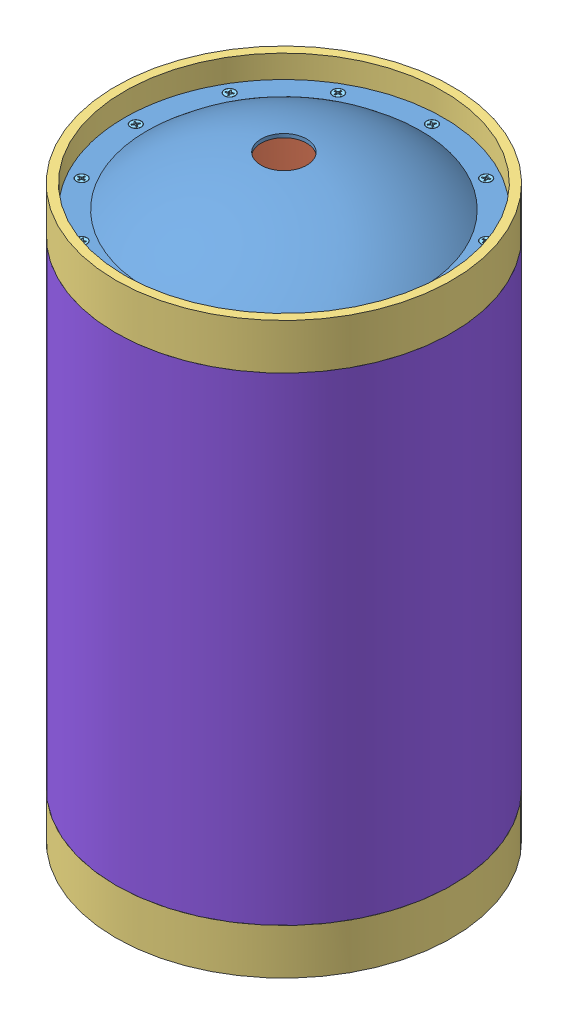
SolidWorks assembly Cryo Tank, configuration Default. Lengths in mm.
Overall size (93.73 173.79 93.73).
34 component instances, 8 part files, 29 mates.
Components (placement in the parent):
- End Cap-1: End Cap [Default] at origin size (88.9 15.46 88.9)
- Liner-1: Liner [Default] at (0 -4.7625 0) size (79.25 133.35 79.25)
- Main Ring-1: Main Ring [Default] at (0 -1.5875 0) size (93.73 25.4 93.73)
- Ring Seal-1: Ring Seal [Default] at (0 -1.5875 0) size (88.9 1.59 88.9)
- Main Ring-2: Main Ring [Default] at (0 -141.2875 0) x (-1 0 0) z (0 0 1) size (93.73 25.4 93.73)
- Ring Seal-2: Ring Seal [Default] at (0 -142.875 0) size (88.9 1.59 88.9)
- End Cap-2: End Cap [Default] at (0 -142.875 0) x (-1 0 0) z (0 0 1) size (88.9 15.46 88.9)
- 90273A015_ZINC-PLATED STL FLAT HEAD PHIL MACHINE SCREW-1: 90273A015_ZINC-PLATED STL FLAT HEAD PHIL MACHINE SCREW [90273A015] at (-35.7452 0.6985 20.6375) x (1 0 0) z (0 1 0) size (2.84 2.84 8.46)
- 90273A015_ZINC-PLATED STL FLAT HEAD PHIL MACHINE SCREW-2: 90273A015_ZINC-PLATED STL FLAT HEAD PHIL MACHINE SCREW [90273A015] at (-41.275 0.6985 0) x (0.866025 0 0.5) z (0 1 0) size (2.84 2.84 8.46)
- 90273A015_ZINC-PLATED STL FLAT HEAD PHIL MACHINE SCREW-3: 90273A015_ZINC-PLATED STL FLAT HEAD PHIL MACHINE SCREW [90273A015] at (-35.7452 0.6985 -20.6375) x (0.5 0 0.866025) z (0 1 0) size (2.84 2.84 8.46)
- 90273A015_ZINC-PLATED STL FLAT HEAD PHIL MACHINE SCREW-4: 90273A015_ZINC-PLATED STL FLAT HEAD PHIL MACHINE SCREW [90273A015] at (-20.6375 0.6985 -35.7452) x (0 0 1) z (0 1 0) size (2.84 2.84 8.46)
- 90273A015_ZINC-PLATED STL FLAT HEAD PHIL MACHINE SCREW-5: 90273A015_ZINC-PLATED STL FLAT HEAD PHIL MACHINE SCREW [90273A015] at (0 0.6985 -41.275) x (-0.5 0 0.866025) z (0 1 0) size (2.84 2.84 8.46)
- 90273A015_ZINC-PLATED STL FLAT HEAD PHIL MACHINE SCREW-6: 90273A015_ZINC-PLATED STL FLAT HEAD PHIL MACHINE SCREW [90273A015] at (20.6375 0.6985 -35.7452) x (-0.866025 0 0.5) z (0 1 0) size (2.84 2.84 8.46)
- 90273A015_ZINC-PLATED STL FLAT HEAD PHIL MACHINE SCREW-7: 90273A015_ZINC-PLATED STL FLAT HEAD PHIL MACHINE SCREW [90273A015] at (35.7452 0.6985 -20.6375) x (-1 0 0) z (0 1 0) size (2.84 2.84 8.46)
- 90273A015_ZINC-PLATED STL FLAT HEAD PHIL MACHINE SCREW-8: 90273A015_ZINC-PLATED STL FLAT HEAD PHIL MACHINE SCREW [90273A015] at (41.275 0.6985 0) x (-0.866025 0 -0.5) z (0 1 0) size (2.84 2.84 8.46)
- 90273A015_ZINC-PLATED STL FLAT HEAD PHIL MACHINE SCREW-9: 90273A015_ZINC-PLATED STL FLAT HEAD PHIL MACHINE SCREW [90273A015] at (35.7452 0.6985 20.6375) x (-0.5 0 -0.866025) z (0 1 0) size (2.84 2.84 8.46)
- 90273A015_ZINC-PLATED STL FLAT HEAD PHIL MACHINE SCREW-10: 90273A015_ZINC-PLATED STL FLAT HEAD PHIL MACHINE SCREW [90273A015] at (20.6375 0.6985 35.7452) x (0 0 -1) z (0 1 0) size (2.84 2.84 8.46)
- 90273A015_ZINC-PLATED STL FLAT HEAD PHIL MACHINE SCREW-11: 90273A015_ZINC-PLATED STL FLAT HEAD PHIL MACHINE SCREW [90273A015] at (0 0.6985 41.275) x (0.5 0 -0.866025) z (0 1 0) size (2.84 2.84 8.46)
- 90273A015_ZINC-PLATED STL FLAT HEAD PHIL MACHINE SCREW-12: 90273A015_ZINC-PLATED STL FLAT HEAD PHIL MACHINE SCREW [90273A015] at (-20.6375 0.6985 35.7452) x (0.866025 0 -0.5) z (0 1 0) size (2.84 2.84 8.46)
- 90273A015_ZINC-PLATED STL FLAT HEAD PHIL MACHINE SCREW-13: 90273A015_ZINC-PLATED STL FLAT HEAD PHIL MACHINE SCREW [90273A015] at (0 -143.5735 41.275) x (1 0 0) z (0 -1 0) size (2.84 2.84 8.46)
- 90273A015_ZINC-PLATED STL FLAT HEAD PHIL MACHINE SCREW-25: 90273A015_ZINC-PLATED STL FLAT HEAD PHIL MACHINE SCREW [90273A015] at (-20.6375 -143.5735 35.7452) x (0.866025 0 0.5) z (0 -1 0) size (2.84 2.84 8.46)
- 90273A015_ZINC-PLATED STL FLAT HEAD PHIL MACHINE SCREW-26: 90273A015_ZINC-PLATED STL FLAT HEAD PHIL MACHINE SCREW [90273A015] at (-35.7452 -143.5735 20.6375) x (0.5 0 0.866025) z (0 -1 0) size (2.84 2.84 8.46)
- 90273A015_ZINC-PLATED STL FLAT HEAD PHIL MACHINE SCREW-27: 90273A015_ZINC-PLATED STL FLAT HEAD PHIL MACHINE SCREW [90273A015] at (-41.275 -143.5735 0) x (0 0 1) z (0 -1 0) size (2.84 2.84 8.46)
- 90273A015_ZINC-PLATED STL FLAT HEAD PHIL MACHINE SCREW-28: 90273A015_ZINC-PLATED STL FLAT HEAD PHIL MACHINE SCREW [90273A015] at (-35.7452 -143.5735 -20.6375) x (-0.5 0 0.866025) z (0 -1 0) size (2.84 2.84 8.46)
- 90273A015_ZINC-PLATED STL FLAT HEAD PHIL MACHINE SCREW-29: 90273A015_ZINC-PLATED STL FLAT HEAD PHIL MACHINE SCREW [90273A015] at (-20.6375 -143.5735 -35.7452) x (-0.866025 0 0.5) z (0 -1 0) size (2.84 2.84 8.46)
- 90273A015_ZINC-PLATED STL FLAT HEAD PHIL MACHINE SCREW-30: 90273A015_ZINC-PLATED STL FLAT HEAD PHIL MACHINE SCREW [90273A015] at (0 -143.5735 -41.275) x (-1 0 0) z (0 -1 0) size (2.84 2.84 8.46)
- 90273A015_ZINC-PLATED STL FLAT HEAD PHIL MACHINE SCREW-31: 90273A015_ZINC-PLATED STL FLAT HEAD PHIL MACHINE SCREW [90273A015] at (20.6375 -143.5735 -35.7452) x (-0.866025 0 -0.5) z (0 -1 0) size (2.84 2.84 8.46)
- 90273A015_ZINC-PLATED STL FLAT HEAD PHIL MACHINE SCREW-32: 90273A015_ZINC-PLATED STL FLAT HEAD PHIL MACHINE SCREW [90273A015] at (35.7452 -143.5735 -20.6375) x (-0.5 0 -0.866025) z (0 -1 0) size (2.84 2.84 8.46)
- 90273A015_ZINC-PLATED STL FLAT HEAD PHIL MACHINE SCREW-33: 90273A015_ZINC-PLATED STL FLAT HEAD PHIL MACHINE SCREW [90273A015] at (41.275 -143.5735 0) x (0 0 -1) z (0 -1 0) size (2.84 2.84 8.46)
- 90273A015_ZINC-PLATED STL FLAT HEAD PHIL MACHINE SCREW-34: 90273A015_ZINC-PLATED STL FLAT HEAD PHIL MACHINE SCREW [90273A015] at (35.7452 -143.5735 20.6375) x (0.5 0 -0.866025) z (0 -1 0) size (2.84 2.84 8.46)
- 90273A015_ZINC-PLATED STL FLAT HEAD PHIL MACHINE SCREW-35: 90273A015_ZINC-PLATED STL FLAT HEAD PHIL MACHINE SCREW [90273A015] at (20.6375 -143.5735 35.7452) x (0.866025 0 -0.5) z (0 -1 0) size (2.84 2.84 8.46)
- CF Inner Layer-1: CF Inner Layer [Default] at (0 64.2407 0) size (80.52 133.35 80.52)
- Honeycomb Core-1: Honeycomb Core [Default] at (0 -50.3801 0) size (93.22 133.35 93.22)
- CF Outer Layer-1: CF Outer Layer [Default] at (0 15.1434 0) size (93.73 133.35 93.73)
Mates (geometry in assembly coordinates):
- Coincident13: coincident: point of Liner-1; point of assembly
- Coincident14: coincident aligned: plane of Liner-1 through (0 -4.7625 0) normal (0 0 1); plane of assembly through (0 0 0) normal (0 0 1)
- Coincident15: coincident aligned: plane of End Cap-1 through (0 0 0) normal (0 0 1); plane of assembly through (0 0 0) normal (0 0 1)
- Coincident16: coordinate: point of End Cap-1; point of assembly
- Coincident17: coincident anti-aligned: line of ? through (110 0 53.4125) axis (0 0 -1)
- Coincident18: coincident aligned: plane of Ring Seal-1 through (0 -1.5875 0) normal (0 0 1); plane of assembly through (0 0 0) normal (0 0 1)
- Coincident20: coincident anti-aligned: line of ? through (110 0 53.4125) axis (0 0 -1)
- Coincident21: coincident aligned: plane of Main Ring-1 through (0 -1.5875 0) normal (0 0 1); plane of assembly through (0 0 0) normal (0 0 1)
- Coincident22: coincident: unknown of ?
- Coincident23: coincident anti-aligned: line of Ring Seal-2 through (110 0 -87.875) axis (0 0 -1); line of assembly
- Coincident24: coincident aligned: plane of Ring Seal-2 through (0 -142.875 0) normal (0 0 1); plane of assembly through (0 0 0) normal (0 0 1)
- Coincident25: coincident: point of Ring Seal-2; point of assembly
- Coincident26: coincident aligned: line of End Cap-2 through (110 0 -197.875) axis (0 0 1); line of assembly
- Coincident27: coincident aligned: plane of End Cap-2 through (0 -142.875 0) normal (0 0 1); plane of assembly through (0 0 0) normal (0 0 1)
- Coincident28: coincident: point of End Cap-2; point of assembly
- Coincident29: coincident aligned: line of Main Ring-2 through (110 0 -196.2875) axis (0 0 1); line of assembly
- Coincident30: coincident aligned: plane of Main Ring-2 through (0 -141.2875 0) normal (0 0 1); plane of assembly through (0 0 0) normal (0 0 1)
- Coincident31: coincident: point of Main Ring-2; point of assembly
- Coincident32: coincident: unknown of ?
- Coincident33: coincident aligned: plane of End Cap-1 through (-44.45 1.5875 0) normal (0 1 0); plane of 90273A015_ZINC-PLATED STL FLAT HEAD PHIL MACHINE SCREW-1 through (-35.7452 1.5875 19.8755) normal (0 1 0)
- Concentric1: concentric anti-aligned: circle of End Cap-1; circle of 90273A015_ZINC-PLATED STL FLAT HEAD PHIL MACHINE SCREW-1
- Concentric2: concentric anti-aligned: circle of End Cap-2; circle of 90273A015_ZINC-PLATED STL FLAT HEAD PHIL MACHINE SCREW-13
- Coincident34: coincident aligned: plane of End Cap-2 through (44.45 -144.4625 0) normal (0 -1 0); plane of 90273A015_ZINC-PLATED STL FLAT HEAD PHIL MACHINE SCREW-13 through (0 -144.4625 42.037) normal (0 -1 0)
- Coincident35: coincident aligned: line of Main Ring-1 through (110 0 53.4125) axis (0 0 -1); line of CF Inner Layer-1 through (110 0 119.2407) axis (0 0 -1)
- Coincident36: coincident aligned: plane of CF Inner Layer-1 through (0 64.2407 0) normal (0 0 1); plane of assembly through (0 0 0) normal (0 0 1)
- Coincident37: coincident aligned: line of CF Inner Layer-1 through (110 0 119.2407) axis (0 0 -1); line of Honeycomb Core-1 through (110 0 4.6199) axis (0 0 -1)
- Coincident38: coincident aligned: plane of Honeycomb Core-1 through (0 -50.3801 0) normal (0 0 1); plane of assembly through (0 0 0) normal (0 0 1)
- Coincident39: coincident aligned: line of CF Inner Layer-1 through (110 0 119.2407) axis (0 0 -1); line of CF Outer Layer-1 through (110 0 70.1434) axis (0 0 -1)
- Coincident40: coincident aligned: plane of CF Outer Layer-1 through (0 15.1434 0) normal (0 0 1); plane of assembly through (0 0 0) normal (0 0 1)
